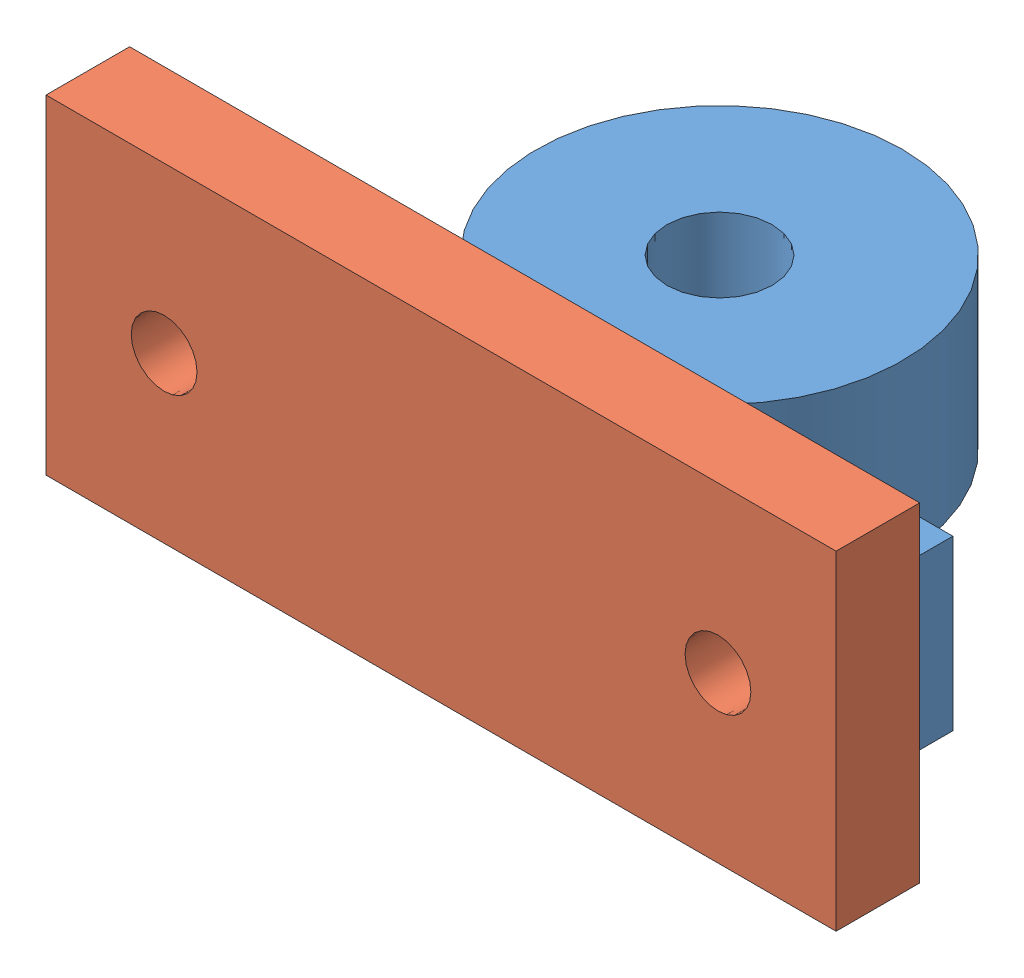
SolidWorks assembly holderAssem, configuration Default. Lengths in mm.
Overall size (60 25 35.05).
2 component instances, 2 part files, 6 mates.
Components (placement in the parent):
- cloudPillowThing-1: cloudPillowThing [Default] at (2.5225 34.0158 36.6371) size (54.7 12.8 28.7)
- pillowCloudHolder-1: pillowCloudHolder [Default] at (-0.1275 52.9158 42.9871) x (1 0 0) z (0 1 0) size (60 6.35 25)
Mates (geometry in assembly coordinates):
- Coincident1: coincident: plane of ? through (-2.1432 28.9075 56.2735) normal (0 1 0); plane of ? through (15.3568 28.9075 32.2735) normal (0 -1 0)
- Concentric1: concentric: cylinder of ? through (15.3568 28.9075 32.2735) axis (0 -1 0) radius 4; cylinder of ? through (15.3568 31.9575 32.2735) axis (0 1 0) radius 4
- Concentric2: concentric aligned: cylinder of ? through (15.3568 28.9075 44.2735) axis (0 -1 0) radius 1.985; cylinder of ? through (15.3568 44.9975 44.2735) axis (0 -1 0) radius 1.985
- Coincident2: coincident: plane of cloudPillowThing-1 through (2.5225 46.8158 36.6371) normal (0 0 1); plane of pillowCloudHolder-1 through (-0.1275 52.9158 36.6371) normal (0 0 -1)
- Concentric3: concentric: cylinder of cloudPillowThing-1 through (50.9025 40.4158 36.6371) axis (0 0 -1) radius 2.5; cylinder of pillowCloudHolder-1 through (50.9025 40.4158 36.6371) axis (0 0 1) radius 2.5
- Concentric4: concentric anti-aligned: cylinder of cloudPillowThing-1 through (8.8425 40.4158 36.6371) axis (0 0 -1) radius 2.5; cylinder of pillowCloudHolder-1 through (8.8425 40.4158 36.6371) axis (0 0 1) radius 2.5
